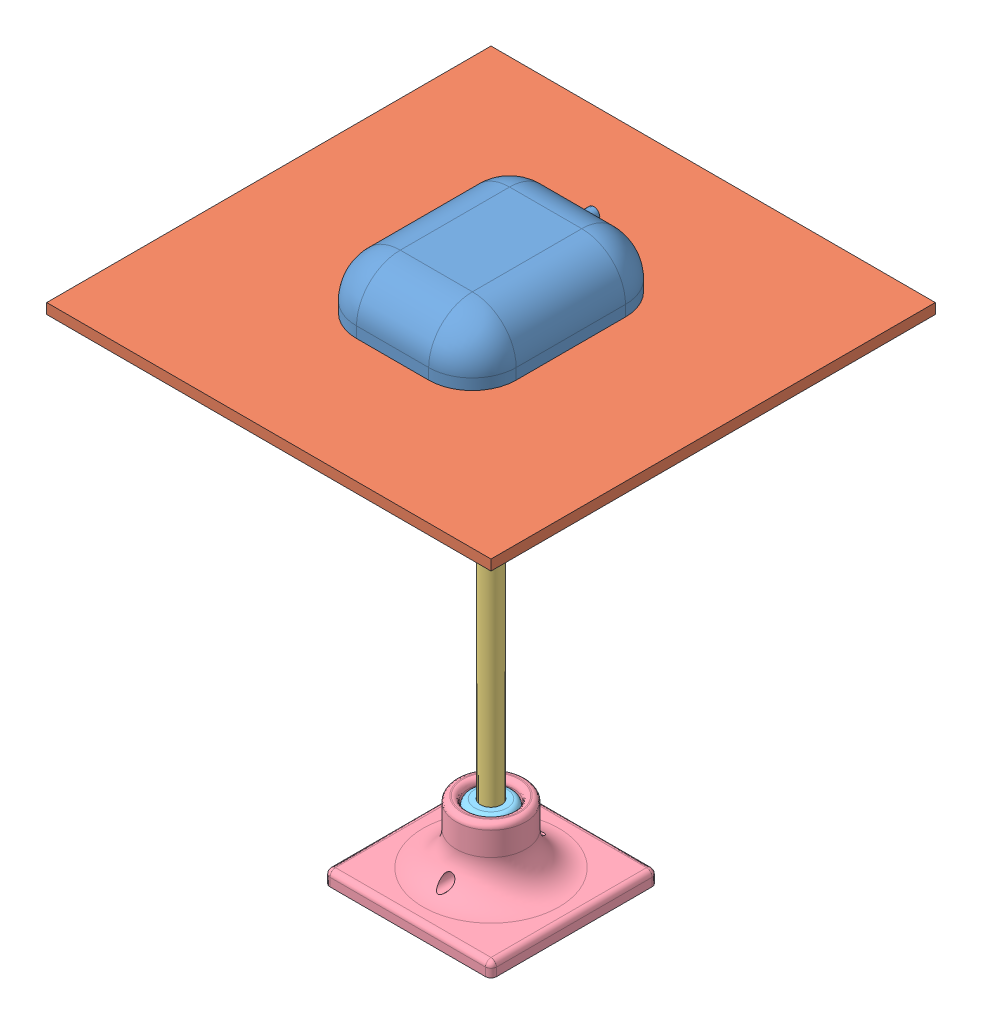
SolidWorks assembly Piksi_GPS_Mount, configuration Default. Lengths in mm.
Overall size (101.6 127.59 101.6).
5 component instances, 5 part files, 14 mates.
Components (placement in the parent):
- GPS_Antenna-1: GPS_Antenna [Default] at (0 127 0) x (0 0 -1) z (1 0 0) size (46 12.5 36.5)
- Piksi_Antenna_TopPlate-1: Piksi_Antenna_TopPlate [Default] at (0 65.209 0) size (101.6 15.08 101.6)
- Mount_Rod-1: Mount_Rod [Default] at (0 19.8438 0) x (0.278544 0 0.960423) z (-0.960423 0 0.278544) size (4.74 101.6 4.74)
- GPS Base-1: GPS Base [Large Hole] at (0 16.6687 0) x (1 0 0) z (0 -1 0) size (38.1 38.1 17.46)
- Pin Coupler-1: Pin Coupler [Large Hole] at (0 19.8438 0) x (1 0 0) z (0 -1 0) size (9.91 9.93 13.65)
Mates (geometry in assembly coordinates):
- Coincident1: coincident anti-aligned: plane of GPS_Antenna-1 through (0 127 0) normal (0 0 -1); plane of assembly through (0 0 0) normal (0 0 1)
- Coincident2: coincident anti-aligned: plane of GPS_Antenna-1 through (0 127 0) normal (0 -1 0); plane of Piksi_Antenna_TopPlate-1 through (0 127 0) normal (0 1 0)
- Coincident3: coincident aligned: plane of GPS_Antenna-1 through (0 127 0) normal (1 0 0); plane of assembly through (0 0 0) normal (1 0 0)
- Concentric2: concentric aligned: cylinder of GPS_Antenna-1 through (-7.25 127 15.6) axis (0 -1 0) radius 1.025; cylinder of Piksi_Antenna_TopPlate-1 through (-7.25 124.6188 15.6) axis (0 -1 0) radius 1.397
- Concentric3: concentric aligned: cylinder of GPS_Antenna-1 through (7.65 127 -14.1) axis (0 -1 0) radius 1.025; cylinder of Piksi_Antenna_TopPlate-1 through (7.65 124.6188 -14.1) axis (0 -1 0) radius 1.397
- Distance1: distance = 127 mm aligned: plane of assembly through (0 0 0) normal (0 1 0); plane of GPS_Antenna-1
- Concentric4: concentric aligned: cylinder of Piksi_Antenna_TopPlate-1 through (0 111.9188 0) axis (0 -1 0) radius 1.9844; cylinder of Mount_Rod-1 through (0 121.4438 0) axis (0 -1 0) radius 2.3685
- Coincident5: coincident anti-aligned: circle of Piksi_Antenna_TopPlate-1; plane of Mount_Rod-1 through (0 121.4438 0) normal (0 1 0)
- Concentric5: concentric aligned: cylinder of Mount_Rod-1 through (0 121.4438 0) axis (0 -1 0) radius 2.3685; circle of GPS Base-1
- Concentric6: concentric aligned: cylinder of Mount_Rod-1 through (0 121.4438 0) axis (0 -1 0) radius 2.3685; cylinder of Pin Coupler-1 through (0 28.7338 0) axis (0 -1 0) radius 2.413
- Coincident7: coincident anti-aligned: plane of GPS Base-1 through (0 15.0812 0) normal (0 1 0); plane of Pin Coupler-1 through (0 15.0812 0) normal (0 -1 0)
- Coincident8: coincident anti-aligned: plane of Mount_Rod-1 through (0 19.8438 0) normal (0 -1 0); plane of Pin Coupler-1 through (0 19.8438 0) normal (0 1 0)
- Coincident10: coincident aligned: plane of GPS Base-1 through (0 16.6687 0) normal (0 0 1); plane of assembly through (0 0 0) normal (0 0 1)
- Coincident11: coincident aligned: plane of Pin Coupler-1 through (0 19.8438 0) normal (0 0 1); plane of assembly through (0 0 0) normal (0 0 1)
